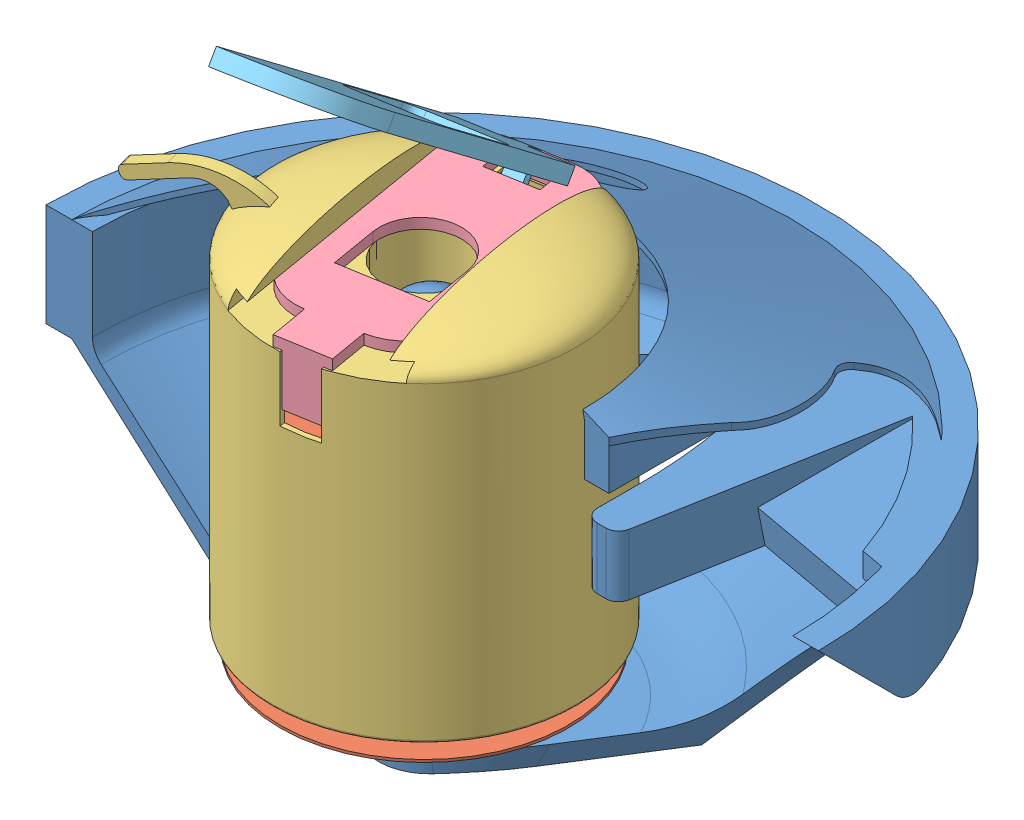
SolidWorks assembly ensamblaje parte delante biela, configuration Predeterminado. Lengths in mm.
Overall size (30 25.89 23.01).
5 component instances, 5 part files, 9 mates.
Components (placement in the parent):
- parte delante biela parte abajo 1-1: parte delante biela parte abajo 1 [Predeterminado] at (-111.0464 -7.6458 6.2037) size (30 14.63 17.59)
- tubo(Parte delante biela)-1: tubo(Parte delante biela) [Predeterminado] at (-111.3579 -1.1003 6.2037) x (0.965887 0 -0.258964) z (0.258964 0 0.965887) size (11.2 10.4 11.2)
- tapa del tubo-1: tapa del tubo [Predeterminado] at (-111.3579 -10.2507 6.2037) x (0.16795 0 0.985795) z (-0.985795 0 0.16795) size (11.88 14.05 14.79)
- tapa para el cubo-1: tapa para el cubo [Predeterminado] at (73.7011 1.8493 224.4257) x (0.16795 0 0.985795) z (-0.985795 0 0.16795) size (11.41 2.4 6)
- tapa para el cubo2-1: tapa para el cubo2 [Predeterminado] at (-73.5174 52.4403 59.7535) x (0.132061 0.617832 0.775141) z (-0.103765 0.78631 -0.609056) size (15.37 4 1.4)
Mates (geometry in assembly coordinates):
- Concéntrica1: concentric aligned: cylinder of parte delante biela parte abajo 1-1 through (-111.3579 -11.6458 6.2037) axis (0 -1 0) radius 2; cylinder of tubo(Parte delante biela)-1 through (-111.3579 -0.9003 6.2037) axis (0 -1 0) radius 2.1
- Concéntrica2: concentric aligned: cylinder of tubo(Parte delante biela)-1 through (-111.3579 -0.9003 6.2037) axis (0 -1 0) radius 2.4; cylinder of tapa del tubo-1 through (-111.3579 1.7493 6.2037) axis (0 -1 0) radius 5.9
- Concéntrica3: concentric aligned: cylinder of tubo(Parte delante biela)-1 through (-111.3579 -11.0003 6.2037) axis (0 -1 0) radius 5.6; cylinder of tapa del tubo-1 through (-111.3579 1.7493 6.2037) axis (0 -1 0) radius 5.7
- Coincidente1: coincident anti-aligned: plane of tapa del tubo-1 through (-112.3488 1.8493 0.3875) normal (0 1 0); plane of tapa para el cubo-1 through (73.7011 1.8493 224.4257) normal (0 -1 0)
- Coincidente2: coincident anti-aligned: plane of tapa del tubo-1 through (-114.3153 -10.2507 6.7076) normal (0.985795 0 -0.16795); plane of tapa para el cubo-1 through (-72.9655 2.2493 249.4133) normal (-0.985795 0 0.16795)
- Paralelo1: parallel aligned: plane of tapa del tubo-1 through (-108.4006 -10.2507 5.6999) normal (-0.985795 0 0.16795); plane of tapa para el cubo2-1 through (-112.7467 9.9196 10.5562) normal (-0.985795 0 0.16795)
- Coincidente4: coincident anti-aligned: line of tapa del tubo-1 through (-112.8087 1.7493 2.3173) axis (0.985795 0 -0.16795); line of tapa para el cubo2-1 through (-111.777 1.7493 2.1415) axis (-0.985795 0 0.16795)
- Distancia1: distance = 0.3 mm anti-aligned: plane of tapa del tubo-1 through (-114.7148 -10.2507 0.7906) normal (0.985795 0 -0.16795); plane of tapa para el cubo2-1 through (-112.7467 9.9196 10.5562) normal (-0.985795 0 0.16795)
- Coincidente7: coincident: line of tapa para el cubo-1 through (-111.1869 2.2493 1.2554) axis (-0.985795 0 0.16795); plane of tapa para el cubo2-1 through (-111.9619 2.6648 1.0563) normal (-0.132061 -0.617832 -0.775141)
